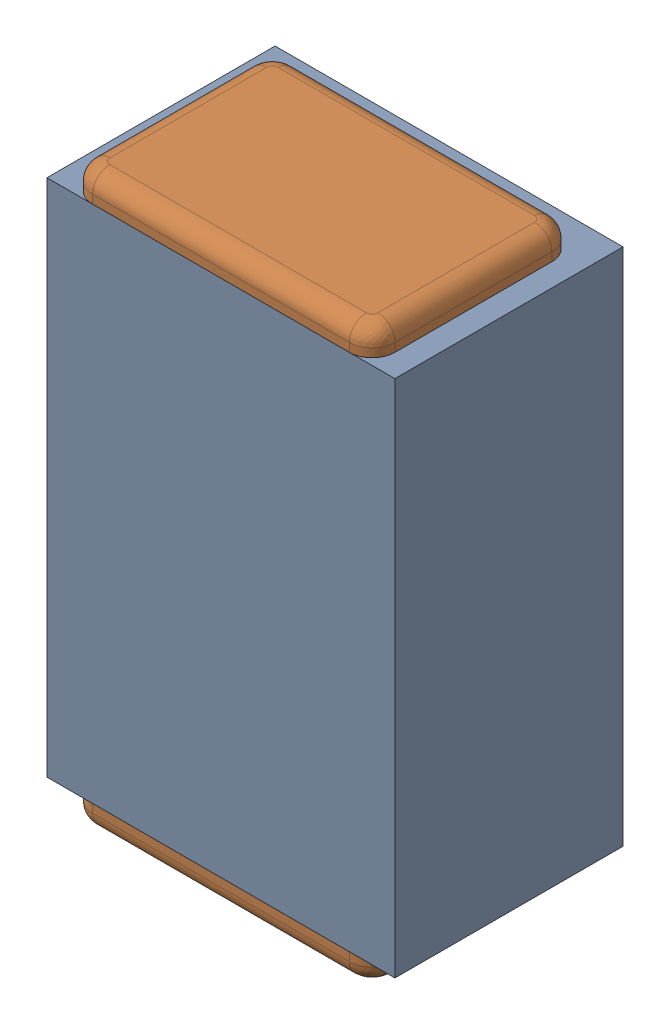
SolidWorks assembly C33, configuration Default. Lengths in mm.
Overall size (0.61 1 0.4).
3 component instances, 2 part files, 0 mates.
Components (placement in the parent):
- 1088881848-1: 1088881848 [Default] at (6.125 31.775 -2.044) size (0.61 0.91 0.4)
  - Extruded-1-1: Extruded-1 [Default] at origin size (0.61 0.91 0.4)
- C0402-1: C0402 [Default] at (6.1251 31.7751 -1.644) x (0 1 0) z (-1 0 0) size (1 0.36 0.54)
